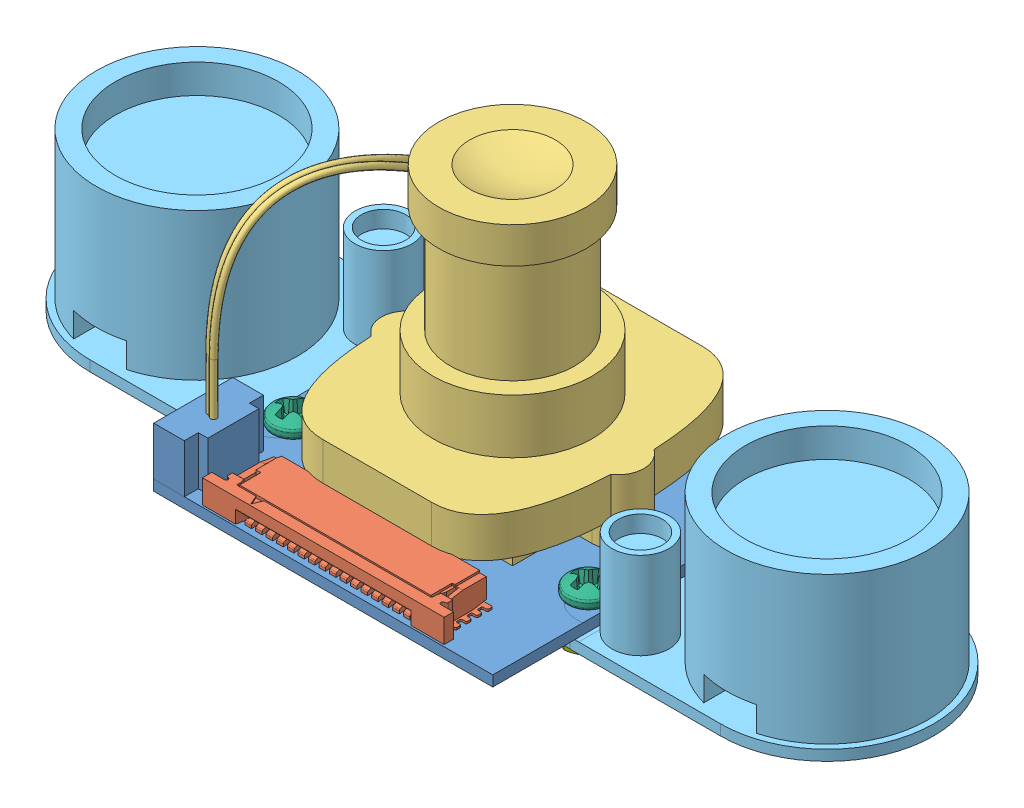
SolidWorks assembly JES Camera Module Kit Embedded IR-CUT Night Vision, configuration Default. Lengths in mm.
Overall size (80 28.97 30.78).
16 component instances, 7 part files, 11 mates.
Components (placement in the parent):
- Raspberry Pi Camera-1: Raspberry Pi Camera [Default] at origin size (32.15 27.14 30.78)
  - camera pcb-1: camera pcb [Default] at origin size (32.15 5.6 26.65)
  - TE-1-84952-5-1: TE-1-84952-5 [Default] at (0 2.315 16.92) size (22.92 2.56 6.54)
  - camera lens-1: camera lens [Default] at (0 1 0) size (27.15 24.9 27.93)
  - 92005A002_METRIC PAN HEAD PHILLIPS MACHINE SCREW-1: 92005A002_METRIC PAN HEAD PHILLIPS MACHINE SCREW [92005A002] at (10 3 0) x (1 0 0) z (0 -1 0) size (3.2 3.2 4.3)
  - 92005A002_METRIC PAN HEAD PHILLIPS MACHINE SCREW-2: 92005A002_METRIC PAN HEAD PHILLIPS MACHINE SCREW [92005A002] at (-10 3 0) x (0.982082 0 -0.188455) z (0 -1 0) size (3.2 3.2 4.3)
- Raspberry PI IR illuminator-1: Raspberry PI IR illuminator [Default] at (-29.88 -1 0.05) x (0 0 -1) z (1 0 0) size (20.24 14.94 27.86)
- Raspberry PI IR illuminator-2: Raspberry PI IR illuminator [Default] at (29.88 -1 0.05) x (0 0 1) z (-1 0 0) size (20.24 14.94 27.86)
- 92005A016_METRIC PAN HEAD PHILLIPS MACHINE SCREW-1: 92005A016_METRIC PAN HEAD PHILLIPS MACHINE SCREW [92005A016] at (14 -3 -6.7) x (1 0 0) z (0 1 0) size (4 4 5.58)
- 90591A265_ZINC PLATED STEEL HEX NUT-1: 90591A265_ZINC PLATED STEEL HEX NUT [90591A265] at (14 -1.8 -6.7) x (1 0 0) z (0 1 0) size (4 4.62 1.83)
- 90591A265_ZINC PLATED STEEL HEX NUT-2: 90591A265_ZINC PLATED STEEL HEX NUT [90591A265] at (14 -1.8 6.8) x (1 0 0) z (0 1 0) size (4 4.62 1.83)
- 90591A265_ZINC PLATED STEEL HEX NUT-3: 90591A265_ZINC PLATED STEEL HEX NUT [90591A265] at (-14 -1.8 -6.7) x (1 0 0) z (0 1 0) size (4 4.62 1.83)
- 90591A265_ZINC PLATED STEEL HEX NUT-4: 90591A265_ZINC PLATED STEEL HEX NUT [90591A265] at (-14 -1.8 6.8) x (1 0 0) z (0 1 0) size (4 4.62 1.83)
- 92005A016_METRIC PAN HEAD PHILLIPS MACHINE SCREW-2: 92005A016_METRIC PAN HEAD PHILLIPS MACHINE SCREW [92005A016] at (14 -3 6.8) x (1 0 0) z (0 1 0) size (4 4 5.58)
- 92005A016_METRIC PAN HEAD PHILLIPS MACHINE SCREW-3: 92005A016_METRIC PAN HEAD PHILLIPS MACHINE SCREW [92005A016] at (-14 -3 -6.7) x (1 0 0) z (0 1 0) size (4 4 5.58)
- 92005A016_METRIC PAN HEAD PHILLIPS MACHINE SCREW-4: 92005A016_METRIC PAN HEAD PHILLIPS MACHINE SCREW [92005A016] at (-14 -3 6.8) x (1 0 0) z (0 1 0) size (4 4 5.58)
Mates (geometry in assembly coordinates):
- Coincident23: coordinate: point of Raspberry Pi Camera-1/camera pcb-1
- Coincident24: coincident anti-aligned: plane of Raspberry Pi Camera-1/camera pcb-1 through (0 0 0) normal (0 -1 0); plane of Raspberry PI IR illuminator-1 through (-29.88 0 0.05) normal (0 1 0)
- Concentric11: concentric aligned: cylinder of Raspberry Pi Camera-1/camera pcb-1 through (-14 1 -6.7) axis (0 -1 0) radius 1; cylinder of Raspberry PI IR illuminator-1 through (-14 0 -6.7) axis (0 -1 0) radius 1.2
- Coincident25: coincident anti-aligned: plane of Raspberry Pi Camera-1/camera pcb-1 through (0 0 0) normal (0 -1 0); plane of Raspberry PI IR illuminator-2 through (29.88 0 0.05) normal (0 1 0)
- Concentric14: concentric aligned: cylinder of Raspberry Pi Camera-1/camera pcb-1 through (14 1 6.8) axis (0 -1 0) radius 1; cylinder of Raspberry PI IR illuminator-2 through (14 0 6.8) axis (0 -1 0) radius 1.2
- Concentric15: concentric aligned: cylinder of Raspberry Pi Camera-1/camera pcb-1 through (14 1 -6.7) axis (0 -1 0) radius 1; cylinder of Raspberry PI IR illuminator-2 through (14 0 -6.7) axis (0 -1 0) radius 1.2
- Concentric16: concentric aligned: cylinder of Raspberry Pi Camera-1/camera pcb-1 through (-14 1 6.8) axis (0 -1 0) radius 1; cylinder of Raspberry PI IR illuminator-1 through (-14 0 6.8) axis (0 -1 0) radius 1.2
- Concentric17: concentric anti-aligned: cylinder of 92005A016_METRIC PAN HEAD PHILLIPS MACHINE SCREW-1 through (14 -3 -6.7) axis (0 1 0) radius 0.7402; cylinder of 90591A265_ZINC PLATED STEEL HEX NUT-1 through (14 -1 -6.7) axis (0 -1 0) radius 1
- Coincident26: coincident anti-aligned: plane of Raspberry Pi Camera-1/camera pcb-1 through (0 1 0) normal (0 1 0); plane of 92005A016_METRIC PAN HEAD PHILLIPS MACHINE SCREW-1 through (14 1 -6.7) normal (0 -1 0)
- Concentric18: concentric anti-aligned: cylinder of Raspberry Pi Camera-1/camera pcb-1 through (14 1 -6.7) axis (0 -1 0) radius 1; cylinder of 92005A016_METRIC PAN HEAD PHILLIPS MACHINE SCREW-1 through (14 -3 -6.7) axis (0 1 0) radius 0.7402
- Coincident27: coincident anti-aligned: plane of Raspberry PI IR illuminator-2 through (29.88 -1 0.05) normal (0 -1 0); plane of 90591A265_ZINC PLATED STEEL HEX NUT-1 through (12 -1 -7.8547) normal (0 1 0)
